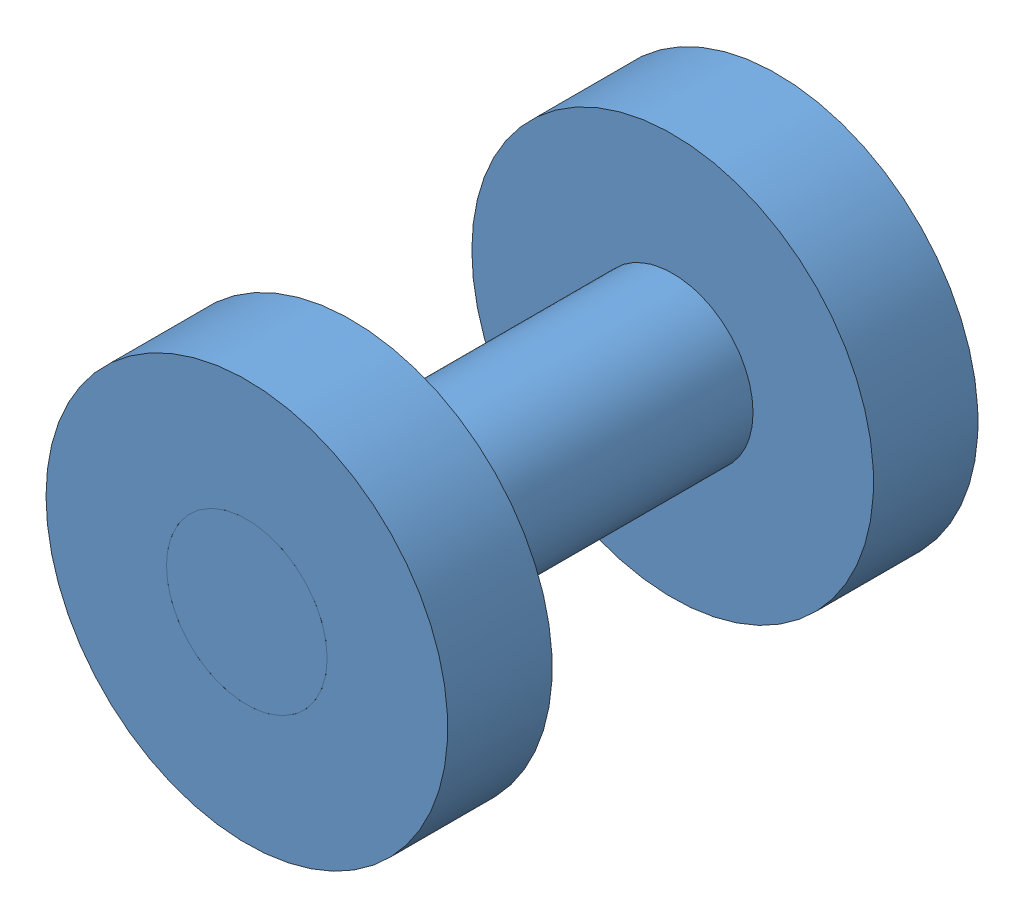
SolidWorks assembly Lift Axle, configuration Default. Lengths in mm.
Overall size (15 15 19.8).
3 component instances, 1 part files, 4 mates.
Components (placement in the parent):
- Lift Axle-6: Lift Axle [Just the End] at (-55.5714 -18.8359 20.8632) size (15 15 3.9)
- Lift Axle-7: Lift Axle [Just the End] at (-55.5714 -18.8359 4.9632) size (15 15 3.9)
- Lift Axle-8: Lift Axle [Just the Middle] at (-55.5714 -18.8359 4.9632) size (6 6 19.8)
Mates (geometry in assembly coordinates):
- Concentric10: concentric anti-aligned: cylinder of Lift Axle-7 through (-55.5714 -18.8359 4.9632) axis (0 0 1) radius 3; cylinder of Lift Axle-8 through (-55.5714 -18.8359 45.9764) axis (0 0 -1) radius 3
- Concentric11: concentric anti-aligned: cylinder of Lift Axle-6 through (-55.5714 -18.8359 20.8632) axis (0 0 1) radius 3; cylinder of Lift Axle-8 through (-55.5714 -18.8359 45.9764) axis (0 0 -1) radius 3
- Coincident9: coincident aligned: plane of Lift Axle-6 through (-55.5714 -18.8359 24.7632) normal (0 0 1); plane of Lift Axle-8 through (-55.5714 -18.8359 24.7632) normal (0 0 1)
- Coincident10: coincident aligned: plane of Lift Axle-7 through (-55.5714 -18.8359 4.9632) normal (0 0 -1); plane of Lift Axle-8 through (-55.5714 -18.8359 4.9632) normal (0 0 -1)
